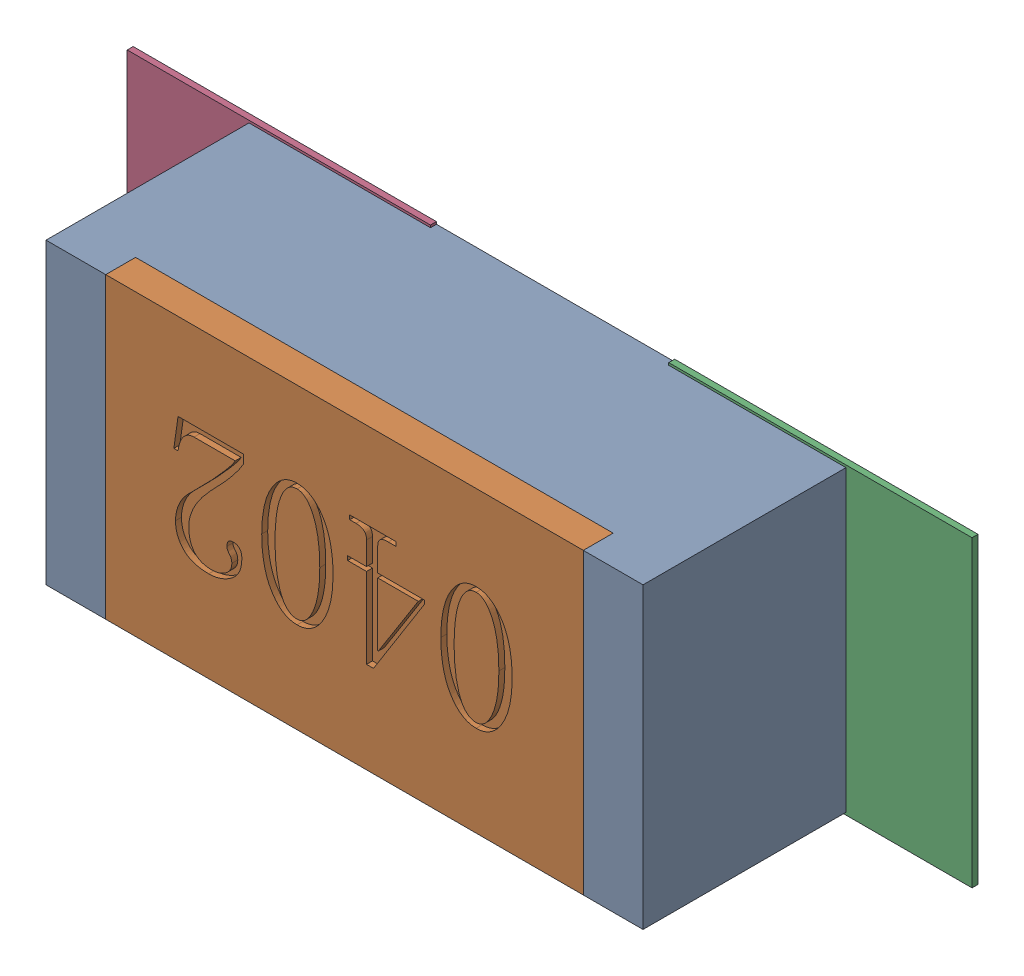
SolidWorks assembly R147, configuration Défaut. Lengths in mm.
Overall size (1.42 0.51 0.35).
5 component instances, 2 part files, 0 mates.
Components (placement in the parent):
- R0402-1: R0402 [Défaut] at (12.2865 -27.9145 0) x (-1 0 0) z (0 0 1) size (1 0.5 0.35)
- 6504207776-1: 6504207776 [Défaut] at (12.7436 -27.9146 0) size (0.51 0.51 0.01)
  - Extruded-1: Extruded [Défaut] at origin size (0.51 0.51 0.01)
- 6504207776-2: 6504207776 [Défaut] at (11.8365 -27.9146 0) size (0.51 0.51 0.01)
  - Extruded-1: Extruded [Défaut] at origin size (0.51 0.51 0.01)
